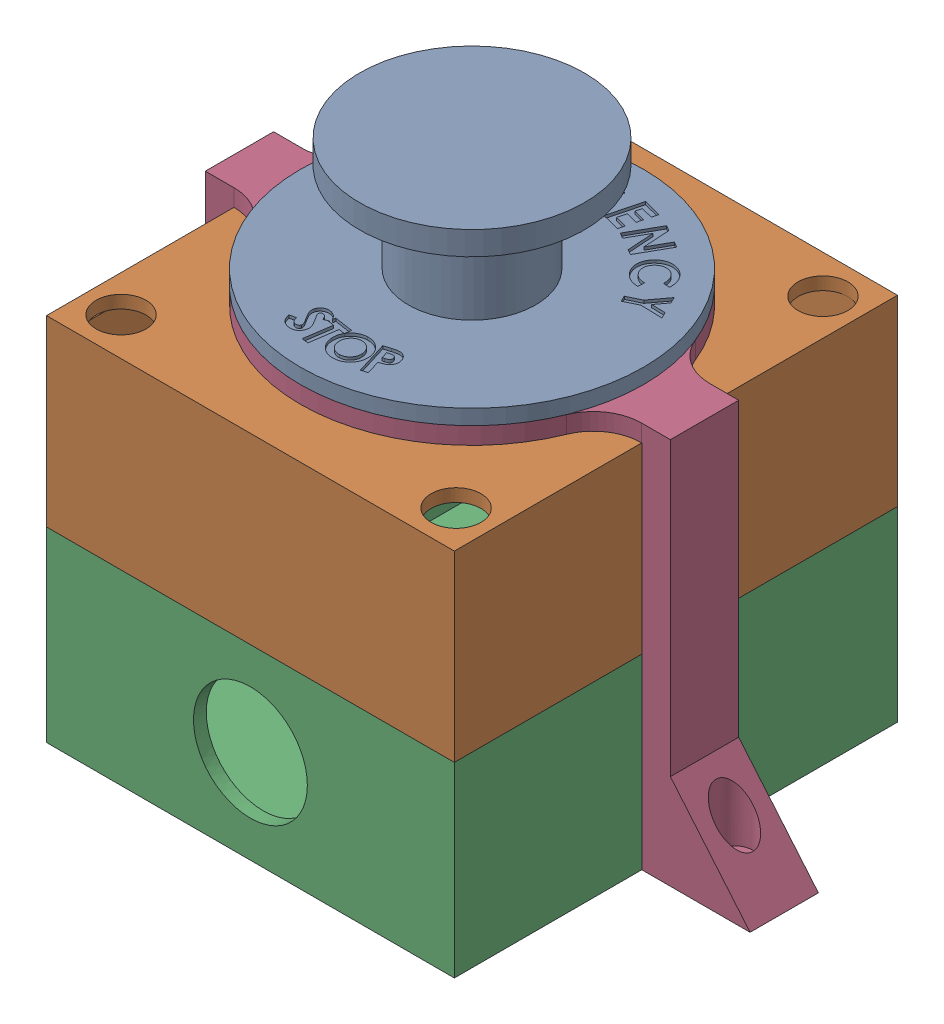
SolidWorks assembly eStopAsm, configuration Default. Lengths in mm.
Overall size (109.7 90.45 77.85).
2 component instances, 2 part files, 3 mates.
Components (placement in the parent):
- eStop-1: eStop [Default] at origin size (71.65 90.45 77.85)
- eStopBracket-2: eStopBracket [Default] at (0 64.95 0) size (109.7 67.95 60.25)
Mates (geometry in assembly coordinates):
- Concentric2: concentric aligned: cylinder of eStop-1 through (0 86.3 0) axis (0 -1 0) radius 11.175; cylinder of eStopBracket-2 through (0 67.95 0) axis (0 -1 0) radius 11.15
- Width1: width anti-aligned: plane of eStopBracket-2 through (0 67.95 0) normal (0 1 0); plane of eStop-1 through (0 64.95 0) normal (0 -1 0); plane of eStopBracket-2 through (0 67.95 0) normal (0 -1 0); plane of eStop-1 through (0 64.95 0) normal (0 1 0)
- Parallel2: parallel aligned: plane of eStop-1 through (35.825 64.95 38.925) normal (1 0 0); plane of eStopBracket-2 through (40.85 16.6846 -76.5564) normal (1 0 0)
